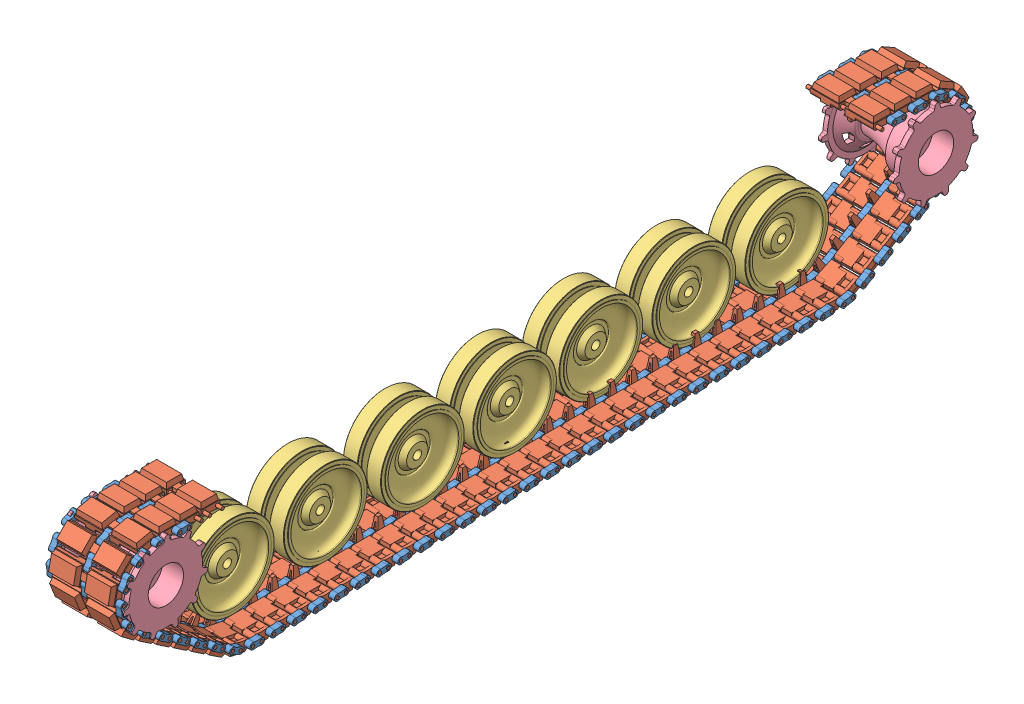
SolidWorks assembly Assem1, configuration Default. Lengths in mm.
Overall size (19.54 38.22 206.79).
119 component instances, 5 part files, 0 mates.
Components (placement in the parent):
- montagem esteira direita 1-1: montagem esteira direita 1 [Valor predeterminado] at (33.2458 -26.8773 87.0038) size (17.75 35.98 204.42)
  - caminho da esteira direita-1: caminho da esteira direita [Valor predeterminado] at origin
  - 3 uniões-1: 3 uniões [Valor predeterminado] at (-39.6 -12.3275 -1.7901) x (1 0 0) z (0 -0.082952 0.996554) size (17.75 1.5 3.5)
  - tracks-1: tracks [Valor predeterminado] at (-39.6 -12.203 -1.785) size (17.75 5.2 4.5)
  - 3 uniões-2: 3 uniões [Valor predeterminado] at (-39.6 -12.3275 -6.7901) x (1 0 0) z (0 -0.082952 0.996554) size (17.75 1.5 3.5)
  - 3 uniões-3: 3 uniões [Valor predeterminado] at (-39.6 -12.3275 -11.7901) x (1 0 0) z (0 -0.082952 0.996554) size (17.75 1.5 3.5)
  - 3 uniões-4: 3 uniões [Valor predeterminado] at (-39.6 -12.3275 -16.7901) x (1 0 0) z (0 -0.082952 0.996554) size (17.75 1.5 3.5)
  - 3 uniões-5: 3 uniões [Valor predeterminado] at (-39.6 -12.3275 -21.7901) x (1 0 0) z (0 -0.082952 0.996554) size (17.75 1.5 3.5)
  - 3 uniões-6: 3 uniões [Valor predeterminado] at (-39.6 -12.3275 -26.7901) x (1 0 0) z (0 -0.082952 0.996554) size (17.75 1.5 3.5)
  - 3 uniões-7: 3 uniões [Valor predeterminado] at (-39.6 -12.3275 -31.7901) x (1 0 0) z (0 -0.082952 0.996554) size (17.75 1.5 3.5)
  - 3 uniões-8: 3 uniões [Valor predeterminado] at (-39.6 -12.3275 -36.7901) x (1 0 0) z (0 -0.082952 0.996554) size (17.75 1.5 3.5)
  - 3 uniões-9: 3 uniões [Valor predeterminado] at (-39.6 -12.3275 -41.7901) x (1 0 0) z (0 -0.082952 0.996554) size (17.75 1.5 3.5)
  - 3 uniões-10: 3 uniões [Valor predeterminado] at (-39.6 -12.3275 -46.7901) x (1 0 0) z (0 -0.082952 0.996554) size (17.75 1.5 3.5)
  - 3 uniões-11: 3 uniões [Valor predeterminado] at (-39.6 -12.3275 -51.7901) x (1 0 0) z (0 -0.082952 0.996554) size (17.75 1.5 3.5)
  - 3 uniões-12: 3 uniões [Valor predeterminado] at (-39.6 -12.3275 -56.7901) x (1 0 0) z (0 -0.082952 0.996554) size (17.75 1.5 3.5)
  - 3 uniões-13: 3 uniões [Valor predeterminado] at (-39.6 -12.3275 -61.7901) x (1 0 0) z (0 -0.082952 0.996554) size (17.75 1.5 3.5)
  - 3 uniões-14: 3 uniões [Valor predeterminado] at (-39.6 -12.3275 -66.7901) x (1 0 0) z (0 -0.082952 0.996554) size (17.75 1.5 3.5)
  - 3 uniões-15: 3 uniões [Valor predeterminado] at (-39.6 -12.3275 -71.7901) x (1 0 0) z (0 -0.082952 0.996554) size (17.75 1.5 3.5)
  - 3 uniões-16: 3 uniões [Valor predeterminado] at (-39.6 -12.3275 -76.7901) x (1 0 0) z (0 -0.082952 0.996554) size (17.75 1.5 3.5)
  - 3 uniões-17: 3 uniões [Valor predeterminado] at (-39.6 -12.3275 -81.7901) x (1 0 0) z (0 -0.082952 0.996554) size (17.75 1.5 3.5)
  - 3 uniões-18: 3 uniões [Valor predeterminado] at (-39.6 -12.3275 -86.7901) x (1 0 0) z (0 -0.082952 0.996554) size (17.75 1.5 3.5)
  - 3 uniões-19: 3 uniões [Valor predeterminado] at (-39.6 -12.3275 -91.7901) x (1 0 0) z (0 -0.082952 0.996554) size (17.75 1.5 3.5)
  - 3 uniões-20: 3 uniões [Valor predeterminado] at (-39.6 -12.3275 -96.7901) x (1 0 0) z (0 -0.082952 0.996554) size (17.75 1.5 3.5)
  - 3 uniões-21: 3 uniões [Valor predeterminado] at (-39.6 -12.3275 -101.7901) x (1 0 0) z (0 -0.082952 0.996554) size (17.75 1.5 3.5)
  - 3 uniões-22: 3 uniões [Valor predeterminado] at (-39.6 -12.3275 -106.7901) x (1 0 0) z (0 -0.082952 0.996554) size (17.75 1.5 3.5)
  - 3 uniões-23: 3 uniões [Valor predeterminado] at (-39.6 -12.3275 -111.7901) x (1 0 0) z (0 -0.082952 0.996554) size (17.75 1.5 3.5)
  - 3 uniões-24: 3 uniões [Valor predeterminado] at (-39.6 -12.3275 -116.7901) x (1 0 0) z (0 -0.082952 0.996554) size (17.75 1.5 3.5)
  - 3 uniões-25: 3 uniões [Valor predeterminado] at (-39.6 -12.3275 -121.7901) x (1 0 0) z (0 -0.082952 0.996554) size (17.75 1.5 3.5)
  - 3 uniões-26: 3 uniões [Valor predeterminado] at (-39.6 -12.3275 -126.7901) x (1 0 0) z (0 -0.082952 0.996554) size (17.75 1.5 3.5)
  - 3 uniões-27: 3 uniões [Valor predeterminado] at (-39.6 -12.3275 -131.7901) x (1 0 0) z (0 -0.082952 0.996554) size (17.75 1.5 3.5)
  - tracks-2: tracks [Valor predeterminado] at (-39.6 -12.203 -6.785) size (17.75 5.2 4.5)
  - tracks-3: tracks [Valor predeterminado] at (-39.6 -12.203 -11.785) size (17.75 5.2 4.5)
  - tracks-4: tracks [Valor predeterminado] at (-39.6 -12.203 -16.785) size (17.75 5.2 4.5)
  - tracks-5: tracks [Valor predeterminado] at (-39.6 -12.203 -21.785) size (17.75 5.2 4.5)
  - tracks-6: tracks [Valor predeterminado] at (-39.6 -12.203 -26.785) size (17.75 5.2 4.5)
  - tracks-7: tracks [Valor predeterminado] at (-39.6 -12.203 -31.785) size (17.75 5.2 4.5)
  - tracks-8: tracks [Valor predeterminado] at (-39.6 -12.203 -36.785) size (17.75 5.2 4.5)
  - tracks-9: tracks [Valor predeterminado] at (-39.6 -12.203 -41.785) size (17.75 5.2 4.5)
  - tracks-10: tracks [Valor predeterminado] at (-39.6 -12.203 -46.785) size (17.75 5.2 4.5)
  - tracks-11: tracks [Valor predeterminado] at (-39.6 -12.203 -51.785) size (17.75 5.2 4.5)
  - tracks-12: tracks [Valor predeterminado] at (-39.6 -12.203 -56.785) size (17.75 5.2 4.5)
  - tracks-13: tracks [Valor predeterminado] at (-39.6 -12.203 -61.785) size (17.75 5.2 4.5)
  - tracks-14: tracks [Valor predeterminado] at (-39.6 -12.203 -66.785) size (17.75 5.2 4.5)
  - tracks-15: tracks [Valor predeterminado] at (-39.6 -12.203 -71.785) size (17.75 5.2 4.5)
  - tracks-16: tracks [Valor predeterminado] at (-39.6 -12.203 -76.785) size (17.75 5.2 4.5)
  - tracks-17: tracks [Valor predeterminado] at (-39.6 -12.203 -81.785) size (17.75 5.2 4.5)
  - tracks-18: tracks [Valor predeterminado] at (-39.6 -12.203 -86.785) size (17.75 5.2 4.5)
  - tracks-19: tracks [Valor predeterminado] at (-39.6 -12.203 -91.785) size (17.75 5.2 4.5)
  - tracks-20: tracks [Valor predeterminado] at (-39.6 -12.203 -96.785) size (17.75 5.2 4.5)
  - tracks-21: tracks [Valor predeterminado] at (-39.6 -12.203 -101.785) size (17.75 5.2 4.5)
  - tracks-22: tracks [Valor predeterminado] at (-39.6 -12.203 -106.785) size (17.75 5.2 4.5)
  - tracks-23: tracks [Valor predeterminado] at (-39.6 -12.203 -111.785) size (17.75 5.2 4.5)
  - tracks-24: tracks [Valor predeterminado] at (-39.6 -12.203 -116.785) size (17.75 5.2 4.5)
  - tracks-25: tracks [Valor predeterminado] at (-39.6 -12.203 -121.785) size (17.75 5.2 4.5)
  - tracks-26: tracks [Valor predeterminado] at (-39.6 -12.203 -126.785) size (17.75 5.2 4.5)
  - tracks-27: tracks [Valor predeterminado] at (-39.6 -12.203 -131.785) size (17.75 5.2 4.5)
  - tracks-28: tracks [Valor predeterminado] at (-39.6 -11.8951 3.1866) x (1 0 0) z (0 0.193729 0.981055) size (17.75 5.2 4.5)
  - 3 uniões-28: 3 uniões [Valor predeterminado] at (-39.6 -12.1727 3.2149) x (1 0 0) z (0 0.008663 0.999962) size (17.75 1.5 3.5)
  - tracks-29: tracks [Valor predeterminado] at (-39.6 4.024 28.4515) x (1 0 0) z (0 0.598283 0.801285) size (17.75 5.2 4.5)
  - tracks-30: tracks [Valor predeterminado] at (-39.6 -9.9699 7.7372) x (1 0 0) z (0 0.557298 0.830313) size (17.75 5.2 4.5)
  - 3 uniões-29: 3 uniões [Valor predeterminado] at (-39.6 -10.2069 7.867) x (1 0 0) z (0 0.399314 0.916814) size (17.75 1.5 3.5)
  - 3 uniões-30: 3 uniões [Valor predeterminado] at (-39.6 -7.1835 11.8888) x (1 0 0) z (0 0.557298 0.830313) size (17.75 1.5 3.5)
  - tracks-31: tracks [Valor predeterminado] at (-39.6 -7.1835 11.8888) x (1 0 0) z (0 0.557298 0.830313) size (17.75 5.2 4.5)
  - tracks-32: tracks [Valor predeterminado] at (-39.6 -4.397 16.0404) x (1 0 0) z (0 0.557298 0.830313) size (17.75 5.2 4.5)
  - tracks-33: tracks [Valor predeterminado] at (-39.6 -1.6105 20.1919) x (1 0 0) z (0 0.557298 0.830313) size (17.75 5.2 4.5)
  - tracks-34: tracks [Valor predeterminado] at (-39.6 1.176 24.3435) x (1 0 0) z (0 0.557298 0.830313) size (17.75 5.2 4.5)
  - 3 uniões-31: 3 uniões [Valor predeterminado] at (-39.6 -4.397 16.0404) x (1 0 0) z (0 0.557298 0.830313) size (17.75 1.5 3.5)
  - 3 uniões-32: 3 uniões [Valor predeterminado] at (-39.6 -1.6105 20.1919) x (1 0 0) z (0 0.557298 0.830313) size (17.75 1.5 3.5)
  - 3 uniões-33: 3 uniões [Valor predeterminado] at (-39.6 1.176 24.3435) x (1 0 0) z (0 0.557298 0.830313) size (17.75 1.5 3.5)
  - 3 uniões-35: 3 uniões [Valor predeterminado] at (-39.6 3.9625 28.4951) x (1 0 0) z (0 0.557298 0.830313) size (17.75 1.5 3.5)
  - tracks-35: tracks [Valor predeterminado] at (-39.6 7.8717 31.4681) x (1 0 0) z (0 0.926852 0.375428) size (17.75 5.2 4.5)
  - tracks-36: tracks [Valor predeterminado] at (-39.6 12.724 31.9236) x (1 0 0) z (0 0.980528 -0.196381) size (17.75 5.2 4.5)
  - 3 uniões-36: 3 uniões [Valor predeterminado] at (-39.6 7.6514 31.8436) x (1 0 0) z (0 0.780007 0.625771) size (17.75 1.5 3.5)
  - 3 uniões-37: 3 uniões [Valor predeterminado] at (-39.6 12.7466 32.3584) x (1 0 0) z (0 0.995623 0.093459) size (17.75 1.5 3.5)
  - 3 uniões-38: 3 uniões [Valor predeterminado] at (-39.6 17.2847 29.9852) x (1 0 0) z (0 0.882837 -0.46968) size (17.75 1.5 3.5)
  - tracks-37: tracks [Valor predeterminado] at (-39.6 17.0266 29.6346) x (1 0 0) z (0 0.71078 -0.703414) size (17.75 5.2 4.5)
  - 3 uniões-39: 3 uniões [Valor predeterminado] at (-39.6 19.7688 25.5068) x (1 0 0) z (0 0.47885 -0.877897) size (17.75 1.5 3.5)
  - 3 uniões-40: 3 uniões [Valor predeterminado] at (-39.6 19.6608 20.3884) x (1 0 0) z (0 -0.002718 -0.999996) size (17.75 1.5 3.5)
  - tracks-38: tracks [Valor predeterminado] at (-39.6 19.3604 25.356) x (1 0 0) z (0 0.206584 -0.978429) size (17.75 5.2 4.5)
  - tracks-39: tracks [Valor predeterminado] at (-39.6 19.6606 20.3884) x (1 0 0) z (0 -0.002819 -0.999996) size (17.75 5.2 4.5)
  - 3 uniões-41: 3 uniões [Valor predeterminado] at (-39.6 19.7329 15.3892) x (1 0 0) z (0 0.021868 -0.999761) size (17.75 1.5 3.5)
  - tracks-40: tracks [Valor predeterminado] at (-39.6 19.6465 15.3884) x (1 0 0) z (0 -0.002819 -0.999996) size (17.75 5.2 4.5)
  - tracks-41: tracks [Valor predeterminado] at (-39.6 19.6324 10.3884) x (1 0 0) z (0 -0.002819 -0.999996) size (17.75 5.2 4.5)
  - 3 uniões-42: 3 uniões [Valor predeterminado] at (-39.6 -12.4454 -136.8075) x (1 0 0) z (0 -0.202998 0.979179) size (17.75 1.5 3.5)
  - 3 uniões-43: 3 uniões [Valor predeterminado] at (-39.6 -11.2277 -141.6617) x (1 0 0) z (0 -0.512318 0.858796) size (17.75 1.5 3.5)
  - tracks-66: tracks [Valor predeterminado] at (-39.6 -11.097 -141.5923) x (1 0 0) z (0 -0.425216 0.905092) size (17.75 5.2 4.5)
  - tracks-67: tracks [Valor predeterminado] at (-39.6 -12.089 -136.7772) x (1 0 0) z (0 0.034582 0.999402) size (17.75 5.2 4.5)
  - tracks-68: tracks [Valor predeterminado] at (-39.6 -8.6661 -145.9557) x (1 0 0) z (0 -0.512318 0.858796) size (17.75 5.2 4.5)
  - 3 uniões-44: 3 uniões [Valor predeterminado] at (-39.6 -8.6661 -145.9557) x (1 0 0) z (0 -0.512318 0.858796) size (17.75 1.5 3.5)
  - 3 uniões-45: 3 uniões [Valor predeterminado] at (-39.6 -6.1045 -150.2497) x (1 0 0) z (0 -0.512318 0.858796) size (17.75 1.5 3.5)
  - 3 uniões-46: 3 uniões [Valor predeterminado] at (-39.6 -3.5429 -154.5436) x (1 0 0) z (0 -0.512318 0.858796) size (17.75 1.5 3.5)
  - tracks-69: tracks [Valor predeterminado] at (-39.6 -6.1045 -150.2497) x (1 0 0) z (0 -0.512318 0.858796) size (17.75 5.2 4.5)
  - tracks-70: tracks [Valor predeterminado] at (-39.6 -3.5429 -154.5436) x (1 0 0) z (0 -0.512318 0.858796) size (17.75 5.2 4.5)
  - tracks-71: tracks [Valor predeterminado] at (-39.6 -0.9813 -158.8376) x (1 0 0) z (0 -0.512318 0.858796) size (17.75 5.2 4.5)
  - tracks-72: tracks [Valor predeterminado] at (-39.6 1.5944 -163.123) x (1 0 0) z (0 -0.521765 0.853089) size (17.75 5.2 4.5)
  - tracks-73: tracks [Valor predeterminado] at (-39.6 4.9755 -166.7004) x (1 0 0) z (0 -0.842395 0.538861) size (17.75 5.2 4.5)
  - tracks-74: tracks [Valor predeterminado] at (-39.6 9.6503 -168.1367) x (1 0 0) z (0 -0.999633 0.027097) size (17.75 5.2 4.5)
  - 3 uniões-47: 3 uniões [Valor predeterminado] at (-39.6 -0.9813 -158.8376) x (1 0 0) z (0 -0.512318 0.858796) size (17.75 1.5 3.5)
  - 3 uniões-48: 3 uniões [Valor predeterminado] at (-39.6 1.376 -163.2856) x (1 0 0) z (0 -0.667407 0.744694) size (17.75 1.5 3.5)
  - 3 uniões-49: 3 uniões [Valor predeterminado] at (-39.6 4.8052 -167.0681) x (1 0 0) z (0 -0.955899 0.293697) size (17.75 1.5 3.5)
  - 3 uniões-50: 3 uniões [Valor predeterminado] at (-39.6 9.6942 -168.5396) x (1 0 0) z (0 -0.970406 -0.241481) size (17.75 1.5 3.5)
  - tracks-75: tracks [Valor predeterminado] at (-39.6 14.3961 -166.9557) x (1 0 0) z (0 -0.87035 -0.492433) size (17.75 5.2 4.5)
  - tracks-76: tracks [Valor predeterminado] at (-39.6 17.8526 -163.496) x (1 0 0) z (0 -0.491603 -0.870819) size (17.75 5.2 4.5)
  - 3 uniões-51: 3 uniões [Valor predeterminado] at (-39.6 18.2291 -163.6457) x (1 0 0) z (0 -0.240556 -0.970635) size (17.75 1.5 3.5)
  - 3 uniões-52: 3 uniões [Valor predeterminado] at (-39.6 14.6415 -167.2782) x (1 0 0) z (0 -0.70677 -0.707444) size (17.75 1.5 3.5)
  - tracks-77: tracks [Valor predeterminado] at (-39.6 19.1155 -158.7491) x (1 0 0) z (0 -0.029601 -0.999562) size (17.75 5.2 4.5)
  - tracks-78: tracks [Valor predeterminado] at (-39.6 19.1698 -153.7498) x (1 0 0) z (0 -0.002819 -0.999996) size (17.75 5.2 4.5)
  - 3 uniões-53: 3 uniões [Valor predeterminado] at (-39.6 19.1557 -158.7498) x (1 0 0) z (0 -0.002819 -0.999996) size (17.75 1.5 3.5)
  - 3 uniões-54: 3 uniões [Valor predeterminado] at (-39.6 19.1698 -153.7498) x (1 0 0) z (0 -0.002819 -0.999996) size (17.75 1.5 3.5)
  - tracks-79: tracks [Valor predeterminado] at (-39.6 19.1838 -148.7498) x (1 0 0) z (0 -0.002819 -0.999996) size (17.75 5.2 4.5)
- roda 1-1: roda 1 [Valor predeterminado] at (-9.2042 -27.8646 41.3263) x (1 0 0) z (0 0.002819 0.999996) size (9.31 19.81 19.81)
- roda 1-2: roda 1 [Valor predeterminado] at (-10.7402 -28.1119 -46.4189) x (1 0 0) z (0 0.002819 0.999996) size (9.31 19.81 19.81)
- roda 1-3: roda 1 [Valor predeterminado] at (-10.7402 -27.988 -2.4391) x (1 0 0) z (0 0.002819 0.999996) size (9.31 19.81 19.81)
- roda 1-4: roda 1 [Valor predeterminado] at (-9.3652 -27.9266 19.3364) x (1 0 0) z (0 0.002819 0.999996) size (9.31 19.81 19.81)
- roda 1-5: roda 1 [Valor predeterminado] at (-9.3652 -27.7383 86.1453) x (1 0 0) z (0 0.002819 0.999996) size (9.31 19.81 19.81)
- roda 1-6: roda 1 [Valor predeterminado] at (-9.3652 -27.8003 64.1554) x (1 0 0) z (0 0.002819 0.999996) size (9.31 19.81 19.81)
- roda 1-7: roda 1 [Valor predeterminado] at (-10.7402 -28.05 -24.429) x (1 0 0) z (0 0.002819 0.999996) size (9.31 19.81 19.81)
- roda traseira-1: roda traseira [Valor predeterminado] at (-23.7005 -17.1501 -71.2755) x (0 0.924225 0.381849) z (-1 0 0) size (19.97 19.78 18)
- roda traseira-2: roda traseira [Valor predeterminado] at (-25.0755 -15.9756 109.61) x (0 0.924225 0.381849) z (-1 0 0) size (19.97 19.78 18)
